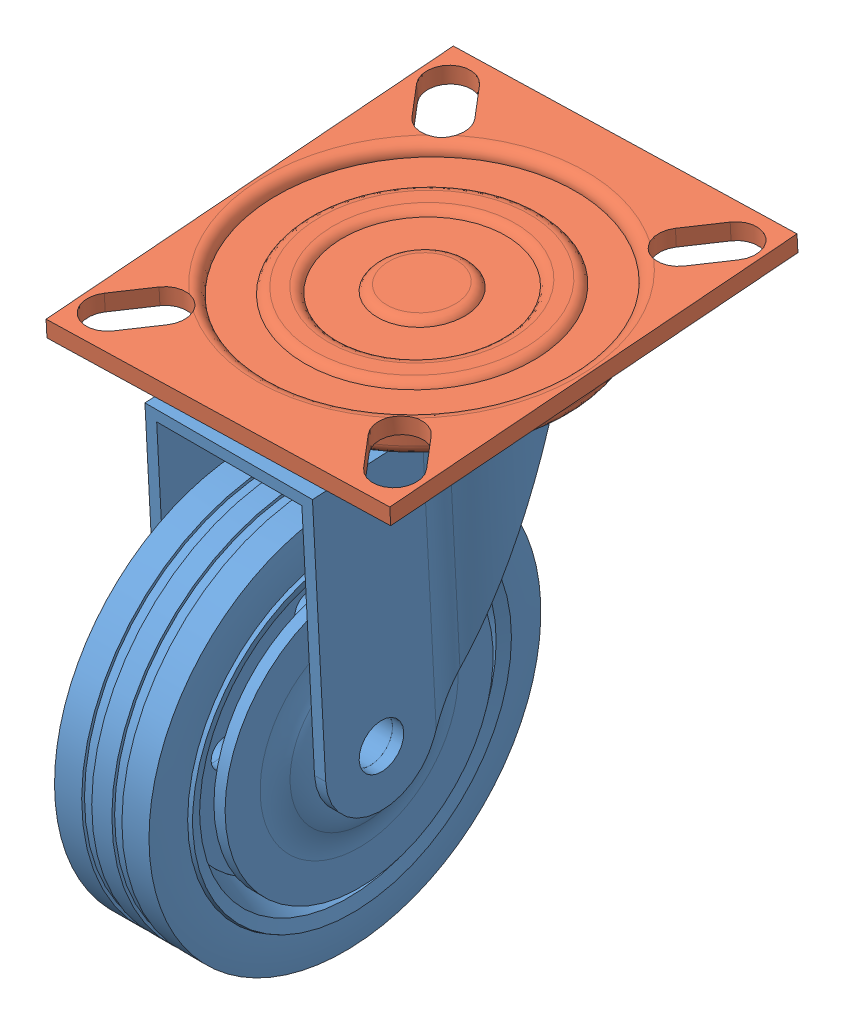
SolidWorks assembly Assem1, configuration Default. Lengths in mm.
Overall size (76.51 91.67 101.43).
2 component instances, 2 part files, 2 mates.
Components (placement in the parent):
- Caster Wheel-1: Caster Wheel [Default] at (24.8103 28.9014 76.6961) size (40 82.38 77.86)
- Caster_segment-1: Caster_segment [Default] at (27.8795 28.9244 76.2589) x (0.99236 0.006482 -0.123209) z (0.123209 0.000401 0.992381) size (67.02 11.45 80.54)
Mates (geometry in assembly coordinates):
- Concentric1: concentric anti-aligned: circle of Caster Wheel-1; circle of Caster_segment-1
- Coincident2: coincident anti-aligned: plane of Caster Wheel-1 through (7.8103 73.8393 79.0603) normal (0 0.998619 0.052537); plane of Caster_segment-1 through (22.8103 75.1527 54.0948) normal (0 -0.998619 -0.052537)
